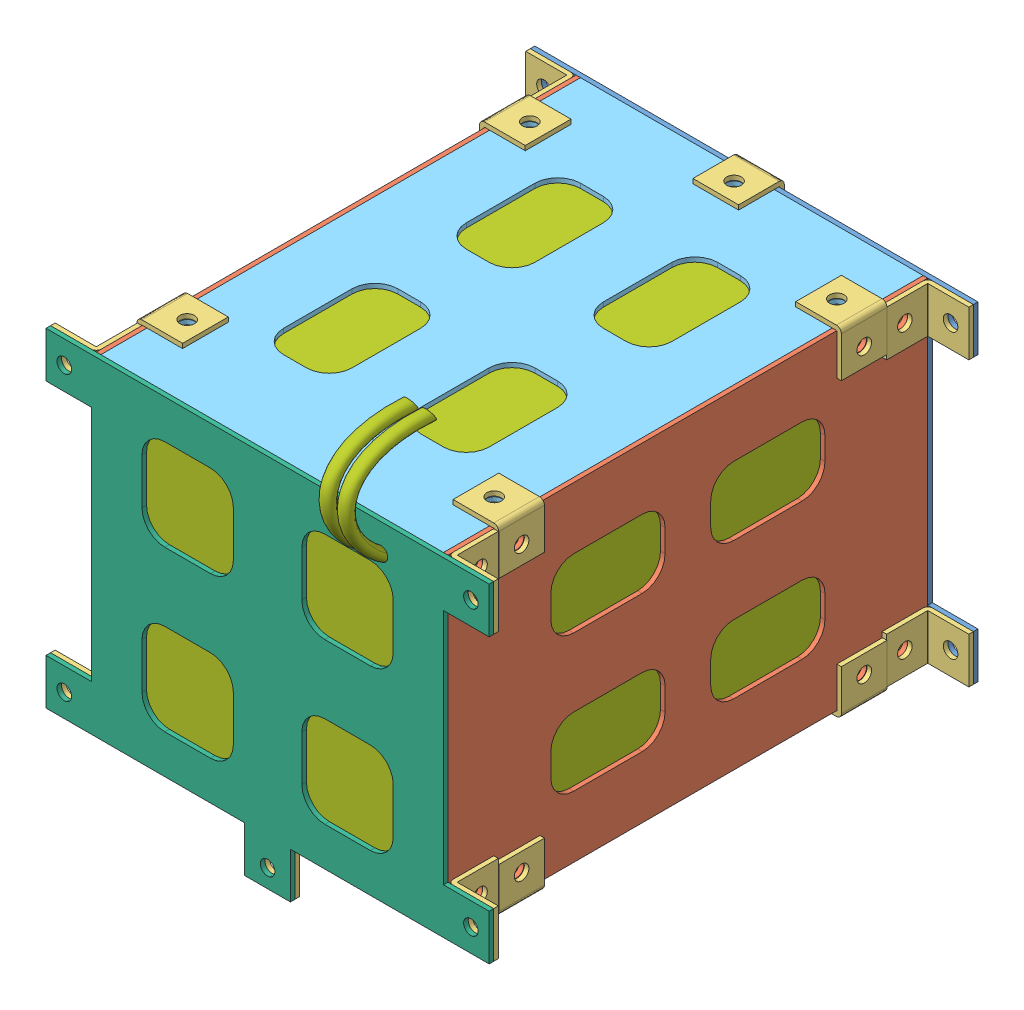
SolidWorks assembly assembly_24V, configuration Default. Lengths in mm.
Overall size (97 98.79 117.43).
26 component instances, 7 part files, 0 mates.
Components (placement in the parent):
- battery_box_24V_base-1: battery_box_24V_base [Default] at origin size (97 82 1)
- battery_box_24V_side1-1: battery_box_24V_side1 [Default] at (37.5 0 53.5) x (0 1 0) z (1 0 0) size (72 105 1)
- connector-1: connector [Default] at (43.5 31 1) x (0 -1 0) z (0 0 1) size (10 10 10)
- connector-2: connector [Default] at (-43.5 -31 106) x (0 -1 0) z (0 0 -1) size (10 10 10)
- connector-3: connector [Default] at (-43.5 31 1) x (0 1 0) z (0 0 1) size (10 10 10)
- connector-4: connector [Default] at (38.5 31 101) x (0 -1 0) z (1 0 0) size (10 10 10)
- battery_box_24V_side1-2: battery_box_24V_side1 [Default] at (-38.5 0 53.5) x (0 1 0) z (1 0 0) size (72 105 1)
- battery_box_24V_front-1: battery_box_24V_front [Default] at (0 -35 53.5) x (1 0 0) z (0 -1 0) size (75 105 1)
- connector-5: connector [Default] at (-43.5 31 106) x (0 -1 0) z (0 0 -1) size (10 10 10)
- connector-6: connector [Default] at (0 32.1 -1.1) x (-1 0 0) z (0 0 1) size (10 10 10)
- connector-7: connector [Default] at (-39.6 32.1 16) x (0 0 1) z (1 0 0) size (10 10 10)
- connector-8: connector [Default] at (-34.6 -37.1 16) x (0 0 1) z (0 1 0) size (10 10 10)
- connector-9: connector [Default] at (0 -41 106) x (1 0 0) z (0 0 -1) size (10 10 10)
- connector-10: connector [Default] at (34.6 -37.1 16) x (0 0 -1) z (0 1 0) size (10 10 10)
- connector-11: connector [Default] at (38.5 -31 101) x (0 -1 0) z (1 0 0) size (10 10 10)
- connector-12: connector [Default] at (-43.5 -31 1) x (0 1 0) z (0 0 1) size (10 10 10)
- connector-13: connector [Default] at (0 -41 1) x (-1 0 0) z (0 0 1) size (10 10 10)
- connector-14: connector [Default] at (43.5 -31 1) x (0 -1 0) z (0 0 1) size (10 10 10)
- connector-15: connector [Default] at (39.6 32.1 16) x (0 0 -1) z (-1 0 0) size (10 10 10)
- connector-16: connector [Default] at (34.6 -37.1 91) x (0 0 -1) z (0 1 0) size (10 10 10)
- connector-17: connector [Default] at (-34.6 37.1 91) x (0 0 -1) z (0 -1 0) size (10 10 10)
- connector-18: connector [Default] at (39.6 32.1 91) x (0 0 -1) z (-1 0 0) size (10 10 10)
- connector-19: connector [Default] at (-39.6 -32.1 91) x (0 0 -1) z (1 0 0) size (10 10 10)
- battery_box_24V_back-1: battery_box_24V_back [Default] at (0 35 53.5) x (1 0 0) z (0 1 0) size (75 105 1)
- battery_box_24V_top-1: battery_box_24V_top [Default] at (0 0 106) size (97 82 1)
- battery_24V-1: battery_24V [Default] at (0 0 1) x (-1 0 0) z (0 0 1) size (75 87.79 115.33)
